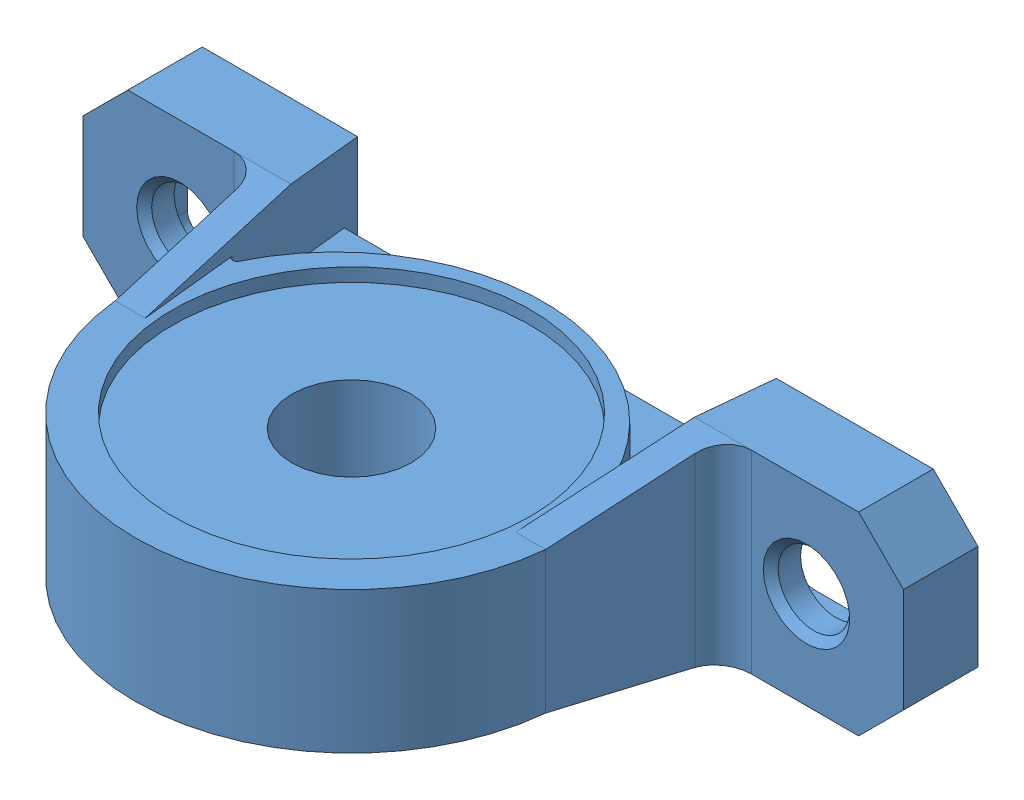
SolidWorks assembly PillowBlockAssembly, configuration Default. Lengths in mm.
Overall size (55 15.35 29).
3 component instances, 2 part files, 3 mates.
Components (placement in the parent):
- Pillow Block KP08-1: Pillow Block KP08 [Default] at origin size (55 15.35 29)
- socket set screw flat point_iso-1: socket set screw flat point_iso [ISO 4026 - M3 x 3-N] at (-8 -6.1 20.7427) x (0 0 -1) z (-0.849695 0.527274 0) size (3 3 3)
- socket set screw flat point_iso-2: socket set screw flat point_iso [ISO 4026 - M3 x 3-N] at (-1.7102 -6.1 14.5) x (-1 0 0) z (0 -0.397455 0.917622) size (3 3 3)
Mates (geometry in assembly coordinates):
- Coincident1: coordinate: point of Pillow Block KP08-1
- Concentric1: concentric anti-aligned: cylinder of Pillow Block KP08-1 through (-8 -6.1 20.8) axis (0 0 -1) radius 1.25; cylinder of socket set screw flat point_iso-1 through (-8 -6.1 33.4427) axis (0 0 1) radius 1.5
- Concentric2: concentric anti-aligned: cylinder of Pillow Block KP08-1 through (-1.7 -6.1 14.5) axis (-1 0 0) radius 1.25; cylinder of socket set screw flat point_iso-2 through (10.9898 -6.1 14.5) axis (1 0 0) radius 1.5
